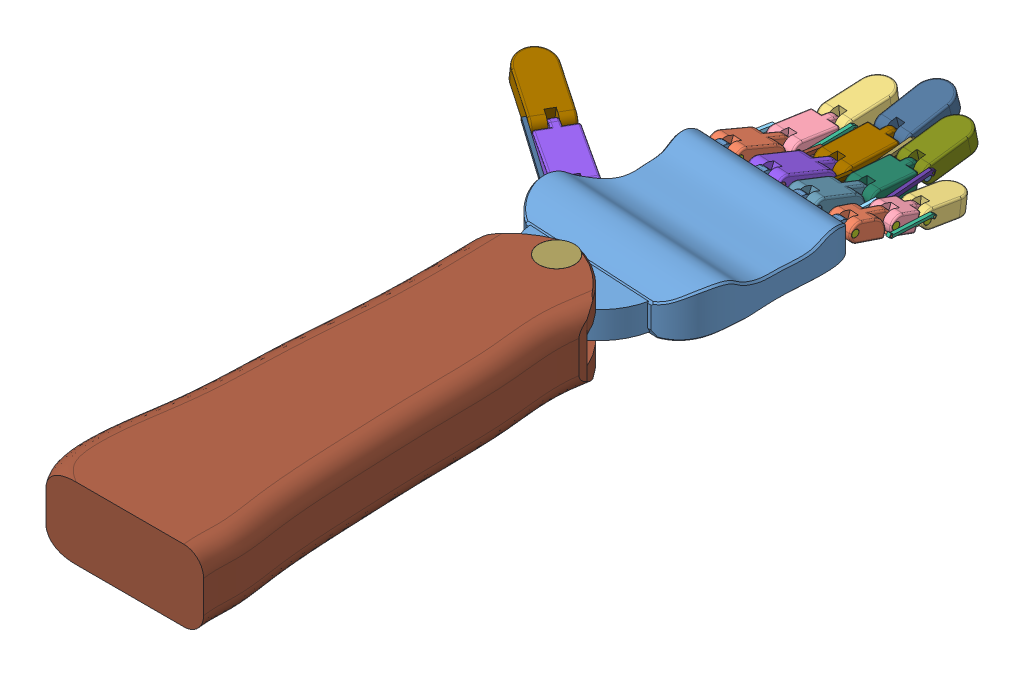
SolidWorks assembly UpdatedHand, configuration Default. Lengths in mm.
Overall size (1869.72 639.15 4644.77).
40 component instances, 30 part files, 87 mates.
Components (placement in the parent):
- palm2-1: palm2 [Default] at (37.6806 51.0353 3.2593) x (0.998503 0 0.054698) z (-0.054698 0 0.998503) size (1069.09 253.19 1333.97)
- bottomIndex2-1: bottomIndex2 [Default] at (-285.8241 139.3632 -641.0227) x (0.998503 0 0.054698) z (0.019807 0.932132 -0.361577) size (192.89 374 100.1)
- topIndex2-1: topIndex2 [Default] at (-256.3881 52.7218 -1178.373) x (0.998503 0 0.054698) z (-0.005683 0.994588 0.103745) size (193.09 335 100.1)
- upIndex2-1: upIndex2 [Default] at (-271.052 59.8082 -914.3416) x (0.998503 0 0.054698) z (0.005424 0.995071 -0.099013) size (193.09 324 100.1)
- link1palm-1: link1palm [Default] at (-371.0339 67.713 -661.4581) x (0.006087 0.993789 -0.111113) z (-0.054358 0.11128 0.992301) size (20 20 387)
- link2-1: link2 [Default] at (-174.9989 19.0255 -1091.8493) x (-0.028141 -0.857504 0.513707) z (-0.046904 0.514477 0.85622) size (202.48 20 293.97)
- WhitepinIndex-1: WhitepinIndex [Default] at (-176.6714 -7.3977 -1079.6011) x (-0.054698 0 0.998503) z (-0.998503 0 -0.054698) size (40 40 170)
- WhitepinIndex-2: WhitepinIndex [Default] at (-191.8933 19.9707 -805.3835) x (-0.054698 0 0.998503) z (-0.998503 0 -0.054698) size (40 40 170)
- WhitepinIndex-3: WhitepinIndex [Default] at (-208.3149 138.0215 -501.9525) x (-0.054698 0 0.998503) z (-0.998503 0 -0.054698) size (40 40 170)
- bottomMiddle2-1: bottomMiddle2 [Default] at (-44.9041 132.2863 -651.2476) x (0.998503 0 0.054698) z (0.019168 0.936589 -0.349906) size (202.89 424 100.1)
- upMiddle2-1: upMiddle2 [Default] at (-27.7017 58.6838 -968.9325) x (0.998503 0 0.054698) z (-0.001065 0.99981 0.019441) size (213.09 374 100.1)
- topMiddle2-1: topMiddle2 [Default] at (-12.199 85.0709 -1255.5897) x (0.998503 0 0.054698) z (-0.013081 0.970982 0.238794) size (213.09 345 100.1)
- llinkMiddle-1: llinkMiddle [Default] at (-139.9144 62.5585 -675.5992) x (0.006642 0.992599 -0.121255) z (-0.054293 0.121437 0.991113) size (20 20 434)
- linkmid2-2: linkmid2 [Default] at (79.47 40.4685 -1173.8987) x (-0.023896 -0.899525 0.436216) z (-0.049202 0.43687 0.898178) size (236.96 20 342.7)
- Whitepinmiddle2-1: Whitepinmiddle2 [Default] at (78.0018 12.6067 -1165.3803) x (-0.054694 0.011327 0.998439) z (-0.998503 0 -0.054698) size (40 40 190)
- Whitepinmiddle2-2: Whitepinmiddle2 [Default] at (-148.4047 138.0215 -498.6706) x (0.054698 0.000118 -0.998503) z (0.998503 0 0.054698) size (40 40 190)
- Whitepinmiddle2-3: Whitepinmiddle2 [Default] at (-129.3422 6.2595 -850.3116) x (0.054694 -0.012385 -0.998426) z (0.998503 0 0.054698) size (40 40 190)
- bottomRing2-1: bottomRing2 [Default] at (177.1278 142.8875 -615.5808) x (0.998503 0 0.054698) z (0.018465 0.941293 -0.337084) size (192.89 374 100.1)
- upRing2-1: upRing2 [Default] at (192.2987 75.0933 -888.8668) x (0.998503 0 0.054698) z (0.001561 0.999593 -0.028495) size (193.09 324 100.1)
- topRing2-1: topRing2 [Default] at (206.8769 88.5798 -1151.3339) x (0.998503 0 0.054698) z (-0.010635 0.980916 0.194139) size (193.09 335 100.1)
- linkRing2-1: linkRing2 [Default] at (288.2537 47.5304 -1068.2413) x (-0.02501 -0.889348 0.456546) z (-0.048645 0.457231 0.888017) size (202.48 20 293.97)
- llink2palmRing-1: llink2palmRing [Default] at (92.1493 72.7692 -636.5808) x (0.004571 0.996502 -0.083449) z (-0.054506 0.083574 0.99501) size (20 20 387)
- WhitepinRing-1: WhitepinRing [Default] at (286.916 20.0911 -1058.4468) x (-0.054698 0 0.998503) z (-0.998503 0 -0.054698) size (40 40 170)
- WhitepinRing-2: WhitepinRing [Default] at (271.6258 27.9674 -782.9831) x (-0.054698 0 0.998503) z (-0.998503 0 -0.054698) size (40 40 170)
- WhitepinRing-3: WhitepinRing [Default] at (254.6415 138.0215 -476.5918) x (-0.054698 0 0.998503) z (-0.998503 0 -0.054698) size (40 40 170)
- bottomlittle2-1: bottomlittle2 [Default] at (404.1404 164.3138 -554.7505) x (0.998503 0 0.054698) z (0.015746 0.957667 -0.287449) size (172.89 274 100.1)
- toplittle2-1: toplittle2 [Default] at (424.8159 59.2736 -932.1799) x (0.998503 0 0.054698) z (0.006497 0.992921 -0.118599) size (173.09 275 100.1)
- uplittle2-1: uplittle2 [Default] at (414.5096 105.0484 -747.6968) x (0.998503 0 0.054698) z (0.016914 0.950987 -0.308769) size (173.09 224 100.1)
- linklittle-1: linklittle [Default] at (329.4239 90.112 -583.9167) x (-0.000804 0.999892 0.014672) z (-0.054692 -0.014694 0.998395) size (20 20 298)
- linklittle2-1: linklittle2 [Default] at (497.2811 41.5772 -865.5718) x (-0.032644 -0.802388 0.59591) z (-0.043889 0.596803 0.801187) size (144.28 20 209.86)
- Whitepinlittle2-1: Whitepinlittle2 [Default] at (336.1754 72.9607 -688.8825) x (0.054698 -0.002295 -0.9985) z (0.998503 0 0.054698) size (40 40 150)
- Whitepinlittle2-2: Whitepinlittle2 [Default] at (345.53 18.5358 -855.9946) x (0.054698 0 -0.998503) z (0.998503 0 0.054698) size (40 40 150)
- Whitepinlittle2-3: Whitepinlittle2 [Default] at (324.5367 138.0215 -472.7629) x (0.054698 0 -0.998503) z (0.998503 0 0.054698) size (40 40 150)
- bottomthumb2-1: bottomthumb2 [Default] at (-626.5124 214.0172 42.889) x (0.500115 0 -0.865959) z (0.154719 0.983909 0.089355) size (202.17 424 100.1)
- topThumb2-1: topThumb2 [Default] at (-919.2606 287.3639 -125.9502) x (0.500115 0 -0.865959) z (0.235918 0.962174 0.136249) size (223.09 400 100.1)
- llink2palmThumb-1: llink2palmThumb [Default] at (-712.251 164.9516 110.0063) x (0.297456 0.939153 0.171789) z (0.813268 -0.3435 0.469685) size (20 20 462)
- Whitepinlittle2-4: Whitepinlittle2 [Default] at (-801.9003 205.2007 -115.9109) x (0.865959 0 0.500115) z (-0.500115 0 0.865959) size (40 40 150)
- Whitepinlittle2-5: Whitepinlittle2 [Default] at (-481.4389 138.0215 68.9335) x (0.865959 0 0.500115) z (-0.500115 0 0.865959) size (40 40 150)
- arm2-1: arm2 [Default] at (-40.7023 157.1387 870) size (1268.57 632.71 2564.87)
- armpin2-1: armpin2 [Default] at (-40.7023 -42.8613 690) x (0.549779 0 0.83531) z (0 1 0) size (200 200 400)
Mates (geometry in assembly coordinates):
- Concentric1: concentric anti-aligned: cylinder of palm2-1 through (-520.5092 138.0215 -519.0544) axis (0.998503 0 0.054698) radius 20; cylinder of bottomIndex2-1 through (-208.3149 138.0215 -501.9525) axis (-0.998503 0 -0.054698) radius 20
- Coincident1: coincident anti-aligned: plane of palm2-1 through (-316.8921 188.0215 -530.9348) normal (-0.998503 0 -0.054698); plane of bottomIndex2-1 through (-321.6898 109.5208 -443.3536) normal (0.998503 0 0.054698)
- Concentric2: concentric anti-aligned: cylinder of bottomIndex2-1 through (-361.4391 19.9707 -814.6712) axis (0.998503 0 0.054698) radius 20; cylinder of upIndex2-1 through (-191.8933 19.9707 -805.3835) axis (-0.998503 0 -0.054698) radius 20
- Coincident2: coincident anti-aligned: plane of bottomIndex2-1 through (-255.3941 -8.1678 -743.119) normal (0.998503 0 0.054698); plane of upIndex2-1 through (-254.7961 -24.8248 -754.0356) normal (-0.998503 0 -0.054698)
- Concentric3: concentric anti-aligned: cylinder of topIndex2-1 through (-176.6714 -7.3977 -1079.6011) axis (-0.998503 0 -0.054698) radius 20; cylinder of upIndex2-1 through (-347.7014 -7.3977 -1088.9701) axis (0.998503 0 0.054698) radius 20
- Coincident3: coincident anti-aligned: plane of topIndex2-1 through (-288.9426 -62.3221 -1041.1502) normal (0.998503 0 0.054698); plane of upIndex2-1 through (-289.5537 -52.0941 -1029.9946) normal (-0.998503 0 -0.054698)
- Concentric14: concentric anti-aligned: cylinder of link1palm-1 through (-360.8417 46.8481 -847.5146) axis (-0.998503 0 -0.054698) radius 5.75; cylinder of upIndex2-1 through (-381.8103 46.8481 -848.6633) axis (0.998503 0 0.054698) radius 5.75
- Concentric15: concentric anti-aligned: cylinder of palm2-1 through (-401.7231 88.0215 -481.5008) axis (0.998503 0 0.054698) radius 5.75; cylinder of link1palm-1 through (-380.9542 88.0215 -480.3631) axis (-0.998503 0 -0.054698) radius 5.75
- Concentric16: concentric anti-aligned: cylinder of topIndex2-1 through (-154.0304 19.0255 -1090.7006) axis (-0.998503 0 -0.054698) radius 5.75; cylinder of link2-1 through (-174.9989 19.0255 -1091.8493) axis (0.998503 0 0.054698) radius 5.75
- Concentric17: concentric anti-aligned: cylinder of bottomIndex2-1 through (-172.3559 5.0431 -759.8263) axis (-0.998503 0 -0.054698) radius 5.75; cylinder of link2-1 through (-193.1248 5.0431 -760.964) axis (0.998503 0 0.054698) radius 5.75
- Distance1: distance = 1 mm anti-aligned: plane of link1palm-1 through (-371.0339 67.713 -661.4581) normal (0.998503 0 0.054698); plane of upIndex2-1 through (-349.6636 -52.0941 -1033.2874) normal (-0.998503 0 -0.054698)
- Distance2: distance = 1 mm anti-aligned: plane of link2-1 through (-174.9989 19.0255 -1091.8493) normal (-0.998503 0 -0.054698); plane of topIndex2-1 through (-164.1468 -33.7494 -1308.2356) normal (0.998503 0 0.054698)
- Concentric18: concentric anti-aligned: cylinder of topIndex2-1 through (-176.6714 -7.3977 -1079.6011) axis (-0.998503 0 -0.054698) radius 20; cylinder of WhitepinIndex-1 through (-346.4169 -7.3977 -1088.8997) axis (0.998503 0 0.054698) radius 20
- Coincident6: coincident aligned: plane of topIndex2-1 through (-333.8923 -33.7494 -1317.5342) normal (-0.998503 0 -0.054698); plane of WhitepinIndex-1 through (-346.4169 -7.3977 -1088.8997) normal (-0.998503 0 -0.054698)
- Concentric19: concentric anti-aligned: cylinder of upIndex2-1 through (-191.8933 19.9707 -805.3835) axis (-0.998503 0 -0.054698) radius 20; cylinder of WhitepinIndex-2 through (-361.6388 19.9707 -814.6821) axis (0.998503 0 0.054698) radius 20
- Coincident7: coincident aligned: plane of upIndex2-1 through (-349.6636 -52.0941 -1033.2874) normal (-0.998503 0 -0.054698); plane of WhitepinIndex-2 through (-361.6388 19.9707 -814.6821) normal (-0.998503 0 -0.054698)
- Concentric20: concentric anti-aligned: cylinder of bottomIndex2-1 through (-208.3149 138.0215 -501.9525) axis (-0.998503 0 -0.054698) radius 20; cylinder of WhitepinIndex-3 through (-378.0604 138.0215 -511.2511) axis (0.998503 0 0.054698) radius 20
- Coincident8: coincident aligned: plane of bottomIndex2-1 through (-365.0297 -8.1678 -749.1248) normal (-0.998503 0 -0.054698); plane of WhitepinIndex-3 through (-378.0604 138.0215 -511.2511) normal (-0.998503 0 -0.054698)
- Concentric21: concentric anti-aligned: cylinder of palm2-1 through (-520.5092 138.0215 -519.0544) axis (0.998503 0 0.054698) radius 20; cylinder of bottomMiddle2-1 through (41.3109 138.0215 -488.278) axis (-0.998503 0 -0.054698) radius 20
- Concentric22: concentric anti-aligned: cylinder of bottomMiddle2-1 through (-130.2273 6.2595 -850.3601) axis (0.998503 0 0.054698) radius 20; cylinder of upMiddle2-1 through (60.3734 6.2595 -839.9191) axis (-0.998503 0 -0.054698) radius 20
- Coincident9: coincident anti-aligned: plane of palm2-1 through (-27.3263 188.0215 -515.0724) normal (0.998503 0 0.054698); plane of bottomMiddle2-1 through (-32.1042 108.7136 -427.8522) normal (-0.998503 0 -0.054698)
- Coincident10: coincident anti-aligned: plane of bottomMiddle2-1 through (-13.0929 -22.698 -778.5581) normal (0.998503 0 0.054698); plane of upMiddle2-1 through (-12.2029 -44.7045 -794.8043) normal (-0.998503 0 -0.054698)
- Concentric23: concentric anti-aligned: cylinder of upMiddle2-1 through (-112.5988 12.6067 -1175.8213) axis (0.998503 0 0.054698) radius 20; cylinder of topMiddle2-1 through (78.0018 12.6067 -1165.3803) axis (-0.998503 0 -0.054698) radius 20
- Coincident11: coincident anti-aligned: plane of upMiddle2-1 through (5.3708 -38.3768 -1119.2671) normal (0.998503 0 0.054698); plane of topMiddle2-1 through (6.1051 -47.9 -1132.6724) normal (-0.998503 0 -0.054698)
- Concentric24: concentric anti-aligned: cylinder of upMiddle2-1 through (-149.4271 36.9353 -885.8728) axis (0.998503 0 0.054698) radius 5.75; cylinder of llinkMiddle-1 through (-128.4585 36.9353 -884.7241) axis (-0.998503 0 -0.054698) radius 5.75
- Concentric25: concentric anti-aligned: cylinder of palm2-1 through (-162.0824 88.0215 -468.3734) axis (0.998503 0 0.054698) radius 5.75; cylinder of llinkMiddle-1 through (-151.2985 88.0215 -467.7826) axis (-0.998503 0 -0.054698) radius 5.75
- Concentric26: concentric anti-aligned: cylinder of topMiddle2-1 through (100.4385 40.4685 -1172.75) axis (-0.998503 0 -0.054698) radius 6.5; cylinder of linkmid2-2 through (79.47 40.4685 -1173.8987) axis (0.998503 0 0.054698) radius 5.75
- Concentric27: concentric anti-aligned: cylinder of bottomMiddle2-1 through (69.9362 -9.2226 -795.0988) axis (-0.998503 0 -0.054698) radius 5.75; cylinder of linkmid2-2 through (58.7529 -9.2226 -795.7114) axis (0.998503 0 0.054698) radius 5.75
- Distance3: distance = 1 mm anti-aligned: plane of linkmid2-2 through (79.47 40.4685 -1173.8987) normal (-0.998503 0 -0.054698); plane of topMiddle2-1 through (90.6058 17.8667 -1395.4639) normal (0.998503 0 0.054698)
- Distance4: distance = 1 mm anti-aligned: plane of llinkMiddle-1 through (-139.9144 62.5585 -675.5992) normal (0.998503 0 0.054698); plane of upMiddle2-1 through (-114.2499 -38.3768 -1125.8199) normal (-0.998503 0 -0.054698)
- Concentric28: concentric anti-aligned: cylinder of topMiddle2-1 through (78.0018 12.6067 -1165.3803) axis (-0.998503 0 -0.054698) radius 20; cylinder of Whitepinmiddle2-1 through (-111.7137 12.6067 -1175.7728) axis (0.998503 0 0.054698) radius 20
- Coincident14: coincident aligned: plane of topMiddle2-1 through (90.6058 17.8667 -1395.4639) normal (0.998503 0 0.054698); plane of Whitepinmiddle2-1 through (78.0018 12.6067 -1165.3803) normal (0.998503 0 0.054698)
- Concentric29: concentric anti-aligned: cylinder of bottomMiddle2-1 through (-130.2273 6.2595 -850.3601) axis (0.998503 0 0.054698) radius 20; cylinder of Whitepinmiddle2-3 through (60.3734 6.2595 -839.9191) axis (-0.998503 0 -0.054698) radius 20
- Coincident15: coincident aligned: plane of upMiddle2-1 through (75.4657 -38.3768 -1115.4274) normal (0.998503 0 0.054698); plane of Whitepinmiddle2-3 through (60.3734 6.2595 -839.9191) normal (0.998503 0 0.054698)
- Concentric30: concentric anti-aligned: cylinder of palm2-1 through (-520.5092 138.0215 -519.0544) axis (0.998503 0 0.054698) radius 20; cylinder of Whitepinmiddle2-2 through (41.3109 138.0215 -488.278) axis (-0.998503 0 -0.054698) radius 20
- Coincident16: coincident aligned: plane of bottomMiddle2-1 through (57.002 -22.698 -774.7183) normal (0.998503 0 0.054698); plane of Whitepinmiddle2-2 through (41.3109 138.0215 -488.278) normal (0.998503 0 0.054698)
- Concentric31: concentric anti-aligned: cylinder of palm2-1 through (-520.5092 138.0215 -519.0544) axis (0.998503 0 0.054698) radius 20; cylinder of bottomRing2-1 through (254.6415 138.0215 -476.5918) axis (-0.998503 0 -0.054698) radius 20
- Coincident17: coincident anti-aligned: plane of palm2-1 through (146.0642 188.0215 -505.5741) normal (-0.998503 0 -0.054698); plane of bottomRing2-1 through (141.3085 107.8363 -418.7601) normal (0.998503 0 0.054698)
- Concentric32: concentric anti-aligned: cylinder of bottomRing2-1 through (101.6806 27.9674 -792.2927) axis (0.998503 0 0.054698) radius 20; cylinder of upRing2-1 through (271.6258 27.9674 -782.9831) axis (-0.998503 0 -0.054698) radius 20
- Coincident18: coincident anti-aligned: plane of bottomRing2-1 through (158.2414 -1.8803 -724.2116) normal (-0.998503 0 -0.054698); plane of upRing2-1 through (158.9787 -20.5854 -737.6703) normal (0.998503 0 0.054698)
- Concentric33: concentric anti-aligned: cylinder of upRing2-1 through (115.886 20.0911 -1067.8158) axis (0.998503 0 0.054698) radius 20; cylinder of topRing2-1 through (286.916 20.0911 -1058.4468) axis (-0.998503 0 -0.054698) radius 20
- Coincident19: coincident anti-aligned: plane of upRing2-1 through (174.2142 -28.4332 -1012.1359) normal (-0.998503 0 -0.054698); plane of topRing2-1 through (174.9297 -38.6763 -1025.1981) normal (0.998503 0 0.054698)
- Concentric34: concentric anti-aligned: cylinder of topRing2-1 through (309.422 47.5304 -1067.0817) axis (-0.998503 0 -0.054698) radius 5.75; cylinder of linkRing2-1 through (288.2537 47.5304 -1068.2413) axis (0.998503 0 0.054698) radius 5.75
- Concentric35: concentric anti-aligned: cylinder of bottomRing2-1 through (290.786 11.8818 -737.8533) axis (-0.998503 0 -0.054698) radius 5.75; cylinder of linkRing2-1 through (270.2168 11.8818 -738.9801) axis (0.998503 0 0.054698) radius 5.75
- Distance5: distance = 1 mm anti-aligned: plane of linkRing2-1 through (288.2537 47.5304 -1068.2413) normal (-0.998503 0 -0.054698); plane of upRing2-1 through (283.8498 -28.4332 -1006.1301) normal (0.998503 0 0.054698)
- Concentric36: concentric anti-aligned: cylinder of upRing2-1 through (81.6004 57.099 -824.2828) axis (0.998503 0 0.054698) radius 5.75; cylinder of llink2palmRing-1 through (102.3692 57.099 -823.1451) axis (-0.998503 0 -0.054698) radius 5.75
- Concentric37: concentric anti-aligned: cylinder of palm2-1 through (61.2333 88.0215 -456.1402) axis (0.998503 0 0.054698) radius 5.75; cylinder of llink2palmRing-1 through (82.2018 88.0215 -454.9915) axis (-0.998503 0 -0.054698) radius 5.75
- Distance6: distance = 1 mm anti-aligned: plane of llink2palmRing-1 through (92.1493 72.7692 -636.5808) normal (0.998503 0 0.054698); plane of bottomRing2-1 through (98.1315 -1.8803 -727.5044) normal (-0.998503 0 -0.054698)
- Concentric38: concentric anti-aligned: cylinder of topRing2-1 through (286.916 20.0911 -1058.4468) axis (-0.998503 0 -0.054698) radius 20; cylinder of WhitepinRing-1 through (117.1705 20.0911 -1067.7454) axis (0.998503 0 0.054698) radius 20
- Coincident22: coincident aligned: plane of topRing2-1 through (299.5199 14.7919 -1288.5295) normal (0.998503 0 0.054698); plane of WhitepinRing-1 through (286.916 20.0911 -1058.4468) normal (0.998503 0 0.054698)
- Concentric39: concentric anti-aligned: cylinder of upRing2-1 through (271.6258 27.9674 -782.9831) axis (-0.998503 0 -0.054698) radius 20; cylinder of WhitepinRing-2 through (101.8803 27.9674 -792.2818) axis (0.998503 0 0.054698) radius 20
- Coincident23: coincident aligned: plane of upRing2-1 through (283.8498 -28.4332 -1006.1301) normal (0.998503 0 0.054698); plane of WhitepinRing-2 through (271.6258 27.9674 -782.9831) normal (0.998503 0 0.054698)
- Concentric40: concentric anti-aligned: cylinder of bottomRing2-1 through (254.6415 138.0215 -476.5918) axis (-0.998503 0 -0.054698) radius 20; cylinder of WhitepinRing-3 through (84.896 138.0215 -485.8904) axis (0.998503 0 0.054698) radius 20
- Coincident24: coincident aligned: plane of bottomRing2-1 through (267.877 -1.8803 -718.2058) normal (0.998503 0 0.054698); plane of WhitepinRing-3 through (254.6415 138.0215 -476.5918) normal (0.998503 0 0.054698)
- Concentric41: concentric anti-aligned: cylinder of palm2-1 through (-520.5092 138.0215 -519.0544) axis (0.998503 0 0.054698) radius 20; cylinder of bottomlittle2-1 through (474.3121 138.0215 -464.5583) axis (-0.998503 0 -0.054698) radius 20
- Coincident25: coincident anti-aligned: plane of palm2-1 through (425.645 188.0215 -490.2587) normal (0.998503 0 0.054698); plane of bottomlittle2-1 through (420.9805 104.5322 -405.1091) normal (-0.998503 0 -0.054698)
- Concentric42: concentric anti-aligned: cylinder of bottomlittle2-1 through (335.2903 72.9607 -688.931) axis (0.998503 0 0.054698) radius 20; cylinder of uplittle2-1 through (485.9508 72.9607 -680.6778) axis (-0.998503 0 -0.054698) radius 20
- Coincident26: coincident anti-aligned: plane of bottomlittle2-1 through (432.5668 39.7592 -620.2724) normal (0.998503 0 0.054698); plane of uplittle2-1 through (432.5791 40.8729 -620.4961) normal (-0.998503 0 -0.054698)
- Concentric43: concentric anti-aligned: cylinder of toplittle2-1 through (495.3055 18.5358 -847.79) axis (-0.998503 0 -0.054698) radius 20; cylinder of uplittle2-1 through (344.2455 18.5358 -856.065) axis (0.998503 0 0.054698) radius 20
- Coincident27: coincident anti-aligned: plane of toplittle2-1 through (392.4148 -25.1714 -797.7581) normal (0.998503 0 0.054698); plane of uplittle2-1 through (391.9566 -13.2427 -789.3936) normal (-0.998503 0 -0.054698)
- Concentric44: concentric anti-aligned: cylinder of uplittle2-1 through (316.2762 92.2133 -727.8358) axis (0.998503 0 0.054698) radius 5.75; cylinder of linklittle-1 through (337.2448 92.2133 -726.6872) axis (-0.998503 0 -0.054698) radius 5.75
- Concentric45: concentric anti-aligned: cylinder of palm2-1 through (300.874 88.0215 -443.0127) axis (0.998503 0 0.054698) radius 5.75; cylinder of linklittle-1 through (321.6428 88.0215 -441.875) axis (-0.998503 0 -0.054698) radius 5.75
- Concentric46: concentric anti-aligned: cylinder of toplittle2-1 through (518.2496 41.5772 -864.4231) axis (-0.998503 0 -0.054698) radius 5.75; cylinder of linklittle2-1 through (497.2811 41.5772 -865.5718) axis (0.998503 0 0.054698) radius 5.75
- Concentric47: concentric anti-aligned: cylinder of bottomlittle2-1 through (505.5597 54.5943 -636.4266) axis (-0.998503 0 -0.054698) radius 5.75; cylinder of linklittle2-1 through (484.7909 54.5943 -637.5643) axis (0.998503 0 0.054698) radius 5.75
- Distance7: distance = 1 mm anti-aligned: plane of linklittle2-1 through (497.2811 41.5772 -865.5718) normal (-0.998503 0 -0.054698); plane of toplittle2-1 through (504.485 -51.8962 -1015.361) normal (0.998503 0 0.054698)
- Distance8: distance = 1 mm anti-aligned: plane of linklittle-1 through (329.4239 90.112 -583.9167) normal (0.998503 0 0.054698); plane of uplittle2-1 through (341.8318 -13.2427 -792.1394) normal (-0.998503 0 -0.054698)
- Concentric48: concentric anti-aligned: cylinder of uplittle2-1 through (344.2455 18.5358 -856.065) axis (0.998503 0 0.054698) radius 20; cylinder of Whitepinlittle2-2 through (495.3055 18.5358 -847.79) axis (-0.998503 0 -0.054698) radius 20
- Coincident30: coincident aligned: plane of toplittle2-1 through (504.485 -51.8962 -1015.361) normal (0.998503 0 0.054698); plane of Whitepinlittle2-2 through (495.3055 18.5358 -847.79) normal (0.998503 0 0.054698)
- Concentric49: concentric anti-aligned: cylinder of bottomlittle2-1 through (335.2903 72.9607 -688.931) axis (0.998503 0 0.054698) radius 20; cylinder of Whitepinlittle2-1 through (485.9508 72.9607 -680.6778) axis (-0.998503 0 -0.054698) radius 20
- Coincident31: coincident aligned: plane of uplittle2-1 through (491.6072 -13.2427 -783.9347) normal (0.998503 0 0.054698); plane of Whitepinlittle2-1 through (485.9508 72.9607 -680.6778) normal (0.998503 0 0.054698)
- Concentric50: concentric anti-aligned: cylinder of palm2-1 through (-520.5092 138.0215 -519.0544) axis (0.998503 0 0.054698) radius 20; cylinder of Whitepinlittle2-3 through (474.3121 138.0215 -464.5583) axis (-0.998503 0 -0.054698) radius 20
- Coincident32: coincident aligned: plane of bottomlittle2-1 through (482.6917 39.7592 -617.5266) normal (0.998503 0 0.054698); plane of Whitepinlittle2-3 through (474.3121 138.0215 -464.5583) normal (0.998503 0 0.054698)
- Concentric51: concentric aligned: cylinder of palm2-1 through (-481.939 138.0215 69.7995) axis (-0.500115 0 0.865959) radius 20; cylinder of bottomthumb2-1 through (-456.4331 138.0215 25.6356) axis (-0.500115 0 0.865959) radius 20
- Coincident33: coincident anti-aligned: plane of palm2-1 through (-538.8646 188.0215 122.3778) normal (-0.500115 0 0.865959); plane of bottomthumb2-1 through (-484.0822 79.8926 154.0161) normal (0.500115 0 -0.865959)
- Concentric52: concentric anti-aligned: cylinder of bottomthumb2-1 through (-877.3609 205.2007 14.7506) axis (0.500115 0 -0.865959) radius 20; cylinder of topThumb2-1 through (-776.8946 205.2007 -159.2088) axis (-0.500115 0 0.865959) radius 20
- Coincident34: coincident anti-aligned: plane of bottomthumb2-1 through (-778.6859 146.8932 -73.6342) normal (0.500115 0 -0.865959); plane of topThumb2-1 through (-784.539 143.4702 -77.0145) normal (-0.500115 0 0.865959)
- Concentric53: concentric anti-aligned: cylinder of topThumb2-1 through (-905.8387 242.239 22.6856) axis (0.500115 0 -0.865959) radius 5.75; cylinder of llink2palmThumb-1 through (-895.2363 242.239 4.3273) axis (-0.500115 0 0.865959) radius 5.75
- Concentric54: concentric anti-aligned: cylinder of palm2-1 through (-539.6137 88.0215 231.6501) axis (0.500115 0 -0.865959) radius 5.75; cylinder of llink2palmThumb-1 through (-530.1116 88.0215 215.1969) axis (-0.500115 0 0.865959) radius 5.75
- Distance9: distance = 1 mm anti-aligned: plane of llink2palmThumb-1 through (-712.251 164.9516 110.0063) normal (0.500115 0 -0.865959); plane of bottomthumb2-1 through (-841.1003 146.8932 34.4375) normal (-0.500115 0 0.865959)
- Concentric55: concentric aligned: cylinder of bottomthumb2-1 through (-877.3609 205.2007 14.7506) axis (0.500115 0 -0.865959) radius 20; cylinder of Whitepinlittle2-4 through (-876.9176 205.2007 13.983) axis (0.500115 0 -0.865959) radius 20
- Coincident36: coincident aligned: plane of topThumb2-1 through (-1117.8444 232.012 -125.1589) normal (-0.500115 0 0.865959); plane of Whitepinlittle2-4 through (-876.9176 205.2007 13.983) normal (-0.500115 0 0.865959)
- Concentric56: concentric anti-aligned: cylinder of palm2-1 through (-481.939 138.0215 69.7995) axis (-0.500115 0 0.865959) radius 20; cylinder of Whitepinlittle2-5 through (-556.4562 138.0215 198.8274) axis (0.500115 0 -0.865959) radius 20
- Coincident37: coincident aligned: plane of bottomthumb2-1 through (-841.1003 146.8932 34.4375) normal (-0.500115 0 0.865959); plane of Whitepinlittle2-5 through (-556.4562 138.0215 198.8274) normal (-0.500115 0 0.865959)
- Concentric57: concentric aligned: cylinder of palm2-1 through (-40.7023 43.0187 690) axis (0 1 0) radius 100; cylinder of arm2-1 through (-40.7023 -42.8613 690) axis (0 1 0) radius 100
- Concentric58: concentric anti-aligned: cylinder of palm2-1 through (-40.7023 43.0187 690) axis (0 1 0) radius 100; cylinder of armpin2-1 through (-40.7023 357.1387 690) axis (0 -1 0) radius 100
- Coincident39: coincident anti-aligned: plane of palm2-1 through (-397.289 232.6387 800.6611) normal (0 1 0); plane of arm2-1 through (-390.7023 232.6387 870) normal (0 -1 0)
- Coincident40: coincident aligned: plane of arm2-1 through (-40.7023 -42.8613 870) normal (0 -1 0); plane of armpin2-1 through (-40.7023 -42.8613 690) normal (0 -1 0)
